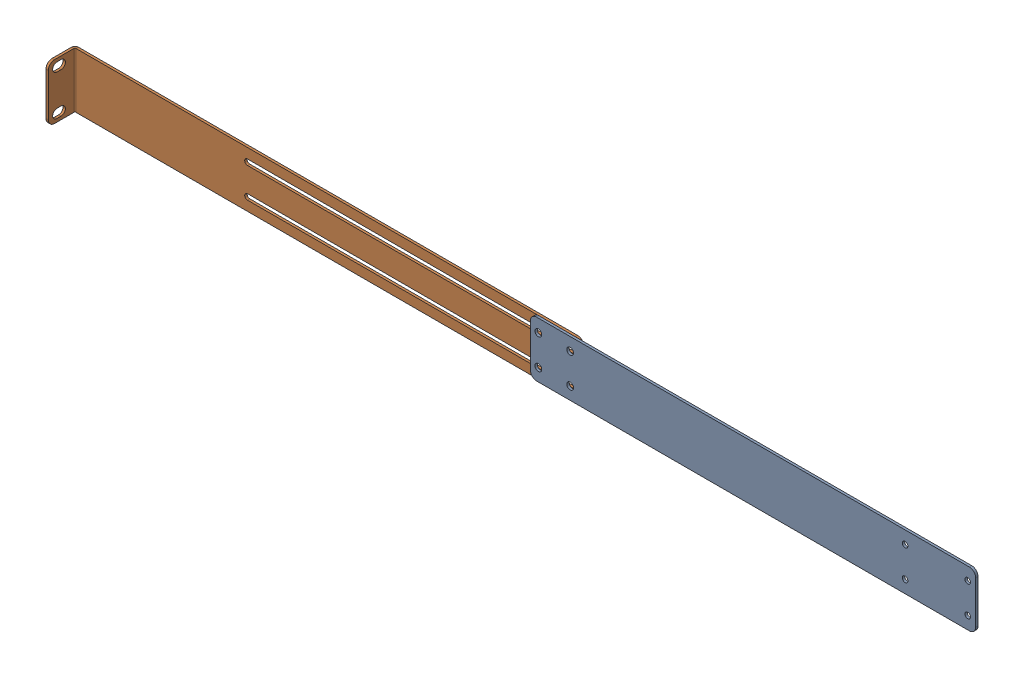
SolidWorks assembly Rear mounting brackets, configuration Default. Lengths in mm.
Overall size (723.12 44.2 23.11).
2 component instances, 2 part files, 2 mates.
Components (placement in the parent):
- Extension plate-1: Extension plate [Default] at origin size (355.6 44.2 1.88)
- Rear ears-1: Rear ears [Default] at (-367.5234 0 -1.8796) size (406.4 44.2 23.11)
Mates (geometry in assembly coordinates):
- Width1: width anti-aligned: plane of Extension plate-1 through (0 44.196 -1.8796) normal (0 1 0); plane of Rear ears-1 through (0 0 -1.8796) normal (0 -1 0); plane of Extension plate-1 through (-367.5234 0 -3.7596) normal (0 -1 0); plane of Rear ears-1 through (-367.5234 44.196 -3.7596) normal (0 1 0)
- Slot2: slot aligned: cylinder of Rear ears-1; cylinder of Extension plate-1 through (6.35 34 -1.8796) axis (0 0 1) radius 2.7051; cylinder of Rear ears-1 through (32.5266 34 -3.7596) axis (0 0 1) radius 2.2225
